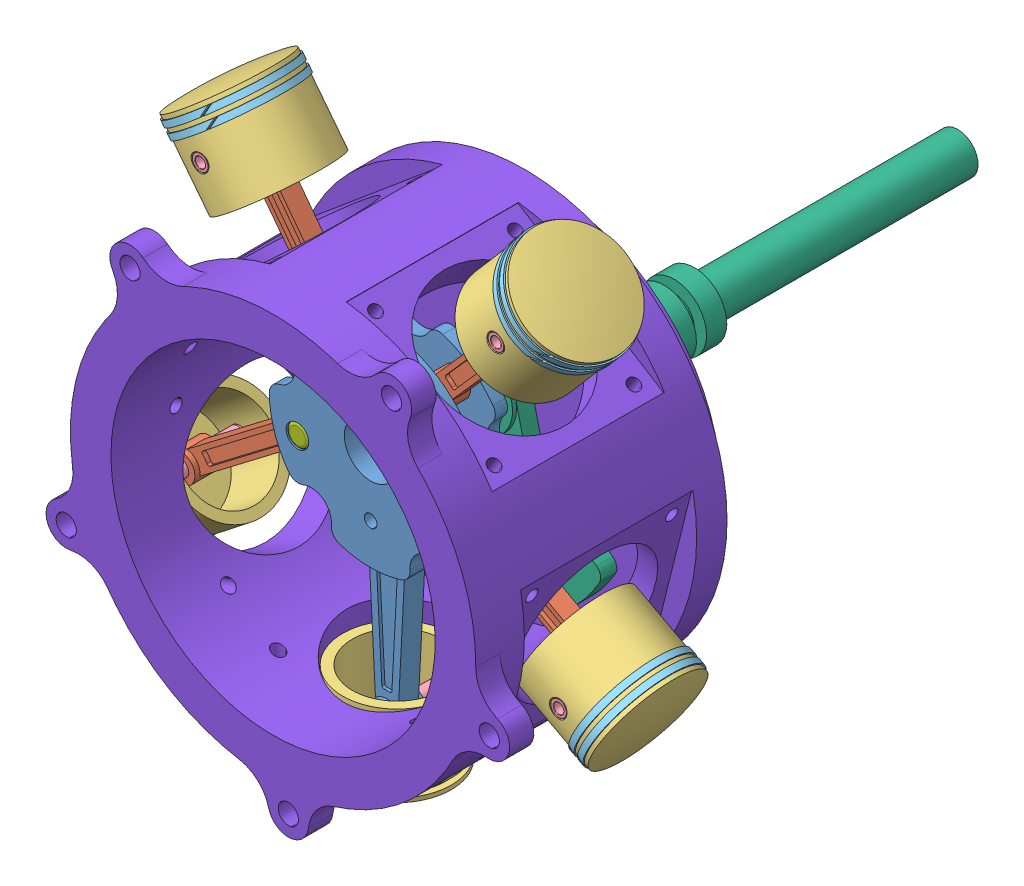
SolidWorks assembly Radial engine, configuration Default. Lengths in mm.
Overall size (283.7 282.07 337.89).
33 component instances, 8 part files, 24 mates.
Components (placement in the parent):
- Connecting Engine-1: Connecting Engine [Default] at (83.762 124.3295 127.1554) size (100 173.8 26)
- Piston assembly-1: Piston assembly [Default] at (71.7323 184.0287 54.7632) x (0.749299 -0.662231 0) z (0 0 1) size (74.22 109.35 74.12)
  - Connecting Rod for piston-1: Connecting Rod for piston [Default] at (44.926 1.0608 72.3922) size (14 94 14)
  - Piston corrected-1: Piston corrected [Default] at (45.1907 61.0625 72.3922) x (0.999912 0.013234 0) z (0 0 1) size (53.6 42 53.6)
  - Connectoing rod-1: Connectoing rod [Default] at (44.926 81.0608 72.3922) x (1 0 0) z (0 -1 0) size (8 53 8)
  - Piston Ring-1: Piston Ring [Default] at (44.7275 96.0595 72.3922) x (0.888214 0.011756 -0.459279) z (0.459239 0.006078 0.888292) size (55 3 55)
  - Piston Ring-2: Piston Ring [Default] at (44.7937 91.0599 72.3922) x (0.888214 0.011756 -0.459279) z (0.459239 0.006078 0.888292) size (55 3 55)
- Piston assembly-2: Piston assembly [Default] at (26.2475 127.109 54.7632) x (0.797287 0.603601 0) z (0 0 1) size (74.22 109.35 74.12)
  - Connecting Rod for piston-1: Connecting Rod for piston [Default] at (44.926 1.0608 72.3922) size (14 94 14)
  - Piston corrected-1: Piston corrected [Default] at (45.1907 61.0625 72.3922) x (0.999912 0.013234 0) z (0 0 1) size (53.6 42 53.6)
  - Connectoing rod-1: Connectoing rod [Default] at (44.926 81.0608 72.3922) x (1 0 0) z (0 -1 0) size (8 53 8)
  - Piston Ring-1: Piston Ring [Default] at (44.7275 96.0595 72.3922) x (0.888214 0.011756 -0.459279) z (0.459239 0.006078 0.888292) size (55 3 55)
  - Piston Ring-2: Piston Ring [Default] at (44.7937 91.0599 72.3922) x (0.888214 0.011756 -0.459279) z (0.459239 0.006078 0.888292) size (55 3 55)
- Piston assembly-3: Piston assembly [Default] at (75.7148 77.5118 54.7632) x (-0.606544 0.79505 0) z (0 0 1) size (74.22 109.35 74.12)
  - Connecting Rod for piston-1: Connecting Rod for piston [Default] at (44.926 1.0608 72.3922) size (14 94 14)
  - Piston corrected-1: Piston corrected [Default] at (45.1907 61.0625 72.3922) x (0.999912 0.013234 0) z (0 0 1) size (53.6 42 53.6)
  - Connectoing rod-1: Connectoing rod [Default] at (44.926 81.0608 72.3922) x (1 0 0) z (0 -1 0) size (8 53 8)
  - Piston Ring-1: Piston Ring [Default] at (44.7275 96.0595 72.3922) x (0.888214 0.011756 -0.459279) z (0.459239 0.006078 0.888292) size (55 3 55)
  - Piston Ring-2: Piston Ring [Default] at (44.7937 91.0599 72.3922) x (0.888214 0.011756 -0.459279) z (0.459239 0.006078 0.888292) size (55 3 55)
- Piston assembly-4: Piston assembly [Default] at (140.6293 152.4598 54.7632) x (-0.482049 -0.876144 0) z (0 0 1) size (74.22 109.35 74.12)
  - Connecting Rod for piston-1: Connecting Rod for piston [Default] at (44.926 1.0608 72.3922) size (14 94 14)
  - Piston corrected-1: Piston corrected [Default] at (45.1907 61.0625 72.3922) x (0.999912 0.013234 0) z (0 0 1) size (53.6 42 53.6)
  - Connectoing rod-1: Connectoing rod [Default] at (44.926 81.0608 72.3922) x (1 0 0) z (0 -1 0) size (8 53 8)
  - Piston Ring-1: Piston Ring [Default] at (44.7275 96.0595 72.3922) x (0.888214 0.011756 -0.459279) z (0.459239 0.006078 0.888292) size (55 3 55)
  - Piston Ring-2: Piston Ring [Default] at (44.7937 91.0599 72.3922) x (0.888214 0.011756 -0.459279) z (0.459239 0.006078 0.888292) size (55 3 55)
- Piston corrected-1: Piston corrected [Default] at (83.762 26.3295 127.1554) x (-1 0 0) z (0 0 1) size (53.6 42 53.6)
- Connectoing rod-1: Connectoing rod [Default] at (83.762 6.3295 127.1554) x (1 0 0) z (0 -1 0) size (8 53 8)
- Shaft-1: Shaft [Default] at (81.5051 104.4572 -151.8446) x (-0.993613 0.112845 0) z (0 0 -1) size (129.9 108 266)
- Connector Medium-1: Connector Medium [Default] at (61.4262 155.0721 127.1554) x (-0.909559 -0.415575 0) z (0 0 1) size (11 11 26)
- Connector Medium-2: Connector Medium [Default] at (106.0978 155.0721 127.1554) x (-0.923122 -0.384507 0) z (0 0 1) size (11 11 26)
- Connector Medium-3: Connector Medium [Default] at (119.9021 112.5868 127.1554) x (-0.7832 0.62177 0) z (0 0 1) size (11 11 26)
- Connector Medium-4: Connector Medium [Default] at (47.6218 112.5868 127.1554) x (0.473099 0.881009 0) z (0 0 -1) size (11 11 26)
- Crank Case-1: Crank Case [Default] at (81.5051 104.4572 62.046) x (0.997653 0.068468 0) z (0.068468 -0.997653 0) size (229.23 136 220)
Mates (geometry in assembly coordinates):
- Concentric1: concentric aligned: cylinder of Connecting Engine-1 through (106.0978 155.0721 140.1554) axis (0 0 -1) radius 5.5; cylinder of Piston assembly-1/Connecting Rod for piston-1 through (106.0978 155.0721 134.1554) axis (0 0 -1) radius 5.5
- Width1: width aligned: plane of Piston assembly-1/Connecting Rod for piston-1 through (106.0978 155.0721 134.1554) normal (0 0 1); plane of Connecting Engine-1 through (106.0978 155.0721 120.1554) normal (0 0 -1); plane of Piston assembly-1/Connecting Rod for piston-1 through (83.762 123.2295 120.1554) normal (0 0 1); plane of Connecting Engine-1 through (83.762 123.2295 134.1554) normal (0 0 -1)
- Concentric2: concentric aligned: cylinder of Connecting Engine-1 through (61.4262 155.0721 140.1554) axis (0 0 -1) radius 5.5; cylinder of Piston assembly-2/Connecting Rod for piston-1 through (61.4262 155.0721 134.1554) axis (0 0 -1) radius 5.5
- Width2: width anti-aligned: plane of Piston assembly-2/Connecting Rod for piston-1 through (61.4262 155.0721 120.1554) normal (0 0 -1); plane of Connecting Engine-1 through (61.4262 155.0721 134.1554) normal (0 0 1); plane of Piston assembly-2/Connecting Rod for piston-1 through (83.762 123.2295 120.1554) normal (0 0 1); plane of Connecting Engine-1 through (83.762 123.2295 134.1554) normal (0 0 -1)
- Concentric3: concentric aligned: cylinder of Connecting Engine-1 through (47.6218 112.5868 140.1554) axis (0 0 -1) radius 5.6168; cylinder of Piston assembly-3/Connecting Rod for piston-1 through (47.6218 112.5868 134.1554) axis (0 0 -1) radius 5.5
- Width3: width anti-aligned: plane of Piston assembly-3/Connecting Rod for piston-1 through (47.6218 112.5868 134.1554) normal (0 0 1); plane of Connecting Engine-1 through (47.6218 112.5868 120.1554) normal (0 0 -1); plane of Piston assembly-3/Connecting Rod for piston-1 through (83.762 123.2295 134.1554) normal (0 0 -1); plane of Connecting Engine-1 through (83.762 123.2295 120.1554) normal (0 0 1)
- Concentric4: concentric aligned: cylinder of Connecting Engine-1 through (119.9021 112.5868 140.1554) axis (0 0 -1) radius 5.6168; cylinder of Piston assembly-4/Connecting Rod for piston-1 through (119.9021 112.5868 134.1554) axis (0 0 -1) radius 5.5
- Width4: width anti-aligned: plane of Piston assembly-4/Connecting Rod for piston-1 through (119.9021 112.5868 120.1554) normal (0 0 -1); plane of Connecting Engine-1 through (119.9021 112.5868 134.1554) normal (0 0 1); plane of Piston assembly-4/Connecting Rod for piston-1 through (83.762 123.2295 120.1554) normal (0 0 1); plane of Connecting Engine-1 through (83.762 123.2295 134.1554) normal (0 0 -1)
- Concentric5: concentric anti-aligned: cylinder of Piston corrected-1 through (83.762 6.3295 100.3554) axis (0 0 1) radius 4; cylinder of Connectoing rod-1 through (83.762 6.3295 153.6554) axis (0 0 -1) radius 4
- Width5: width: plane of Connectoing rod-1 through (83.762 6.3295 153.6554) normal (0 0 1); plane of Piston corrected-1 through (83.762 6.3295 100.6554) normal (0 0 -1); cylinder of Connectoing rod-1 through (83.762 -40.45 127.1554) axis (0 -1 0) radius 26.8
- Concentric6: concentric aligned: cylinder of Connecting Engine-1 through (83.762 6.3295 134.1554) axis (0 0 -1) radius 4; cylinder of Connectoing rod-1 through (83.762 6.3295 153.6554) axis (0 0 -1) radius 4
- Width6: width: plane of Connecting Engine-1 through (83.762 124.3295 134.1554) normal (0 0 1); plane of Piston corrected-1 through (83.762 124.3295 120.1554) normal (0 0 -1); cylinder of Connecting Engine-1 through (83.762 -3.6705 127.1554) axis (0 1 0) radius 22
- Width7: width: plane of Connecting Engine-1 through (95.2501 123.7271 132.1554) normal (0.998628 -0.052366 0); plane of Piston corrected-1 through (72.2739 123.7271 132.1554) normal (-0.998628 -0.052366 0); cylinder of Connecting Engine-1 through (83.762 -3.6705 127.1554) axis (0 1 0) radius 22
- Concentric7: concentric aligned: cylinder of Connecting Engine-1 through (83.762 124.3295 140.1554) axis (0 0 -1) radius 13; cylinder of Shaft-1 through (83.762 124.3295 114.1554) axis (0 0 -1) radius 13
- Coincident1: coincident anti-aligned: plane of Connecting Engine-1 through (83.762 124.3295 114.1554) normal (0 0 -1); plane of Shaft-1 through (83.762 124.3295 114.1554) normal (0 0 1)
- Concentric8: concentric aligned: cylinder of Connecting Engine-1 through (61.4262 155.0721 140.1554) axis (0 0 -1) radius 5.5; cylinder of Connector Medium-1 through (61.4262 155.0721 140.1554) axis (0 0 -1) radius 5.5
- Width8: width aligned: plane of Connector Medium-1 through (61.4262 155.0721 140.1554) normal (0 0 1); plane of Connecting Engine-1 through (61.4262 155.0721 114.1554) normal (0 0 -1); plane of Connector Medium-1 through (83.762 124.3295 140.1554) normal (0 0 1); plane of Connecting Engine-1 through (83.762 124.3295 114.1554) normal (0 0 -1)
- Concentric9: concentric anti-aligned: cylinder of Connector Medium-4 through (47.6218 112.5868 114.1554) axis (0 0 1) radius 5.5; cylinder of Connecting Engine-1 through (47.6218 112.5868 140.1554) axis (0 0 -1) radius 5.6168
- Width9: width anti-aligned: plane of Connector Medium-4 through (47.6218 112.5868 114.1554) normal (0 0 -1); plane of Connecting Engine-1 through (47.6218 112.5868 140.1554) normal (0 0 1); plane of Connector Medium-4 through (83.762 124.3295 140.1554) normal (0 0 1); plane of Connecting Engine-1 through (83.762 124.3295 114.1554) normal (0 0 -1)
- Concentric10: concentric aligned: cylinder of Connecting Engine-1 through (106.0978 155.0721 140.1554) axis (0 0 -1) radius 5.5; cylinder of Connector Medium-2 through (106.0978 155.0721 140.1554) axis (0 0 -1) radius 5.5
- Width10: width anti-aligned: plane of Connector Medium-2 through (106.0978 155.0721 140.1554) normal (0 0 1); plane of Connecting Engine-1 through (106.0978 155.0721 114.1554) normal (0 0 -1); plane of Connector Medium-2 through (83.762 124.3295 114.1554) normal (0 0 -1); plane of Connecting Engine-1 through (83.762 124.3295 140.1554) normal (0 0 1)
- Concentric11: concentric aligned: cylinder of Connecting Engine-1 through (119.9021 112.5868 140.1554) axis (0 0 -1) radius 5.6168; cylinder of Connector Medium-3 through (119.9021 112.5868 140.1554) axis (0 0 -1) radius 5.5
- Width11: width anti-aligned: plane of Connector Medium-3 through (119.9021 112.5868 140.1554) normal (0 0 1); plane of Connecting Engine-1 through (119.9021 112.5868 114.1554) normal (0 0 -1); plane of Connector Medium-3 through (83.762 124.3295 114.1554) normal (0 0 -1); plane of Connecting Engine-1 through (83.762 124.3295 140.1554) normal (0 0 1)
- Concentric12: concentric aligned: cylinder of Shaft-1 through (81.5051 104.4572 68.1554) axis (0 0 -1) radius 17.5; cylinder of Crank Case-1 through (81.5051 104.4572 186.046) axis (0 0 -1) radius 17.5
